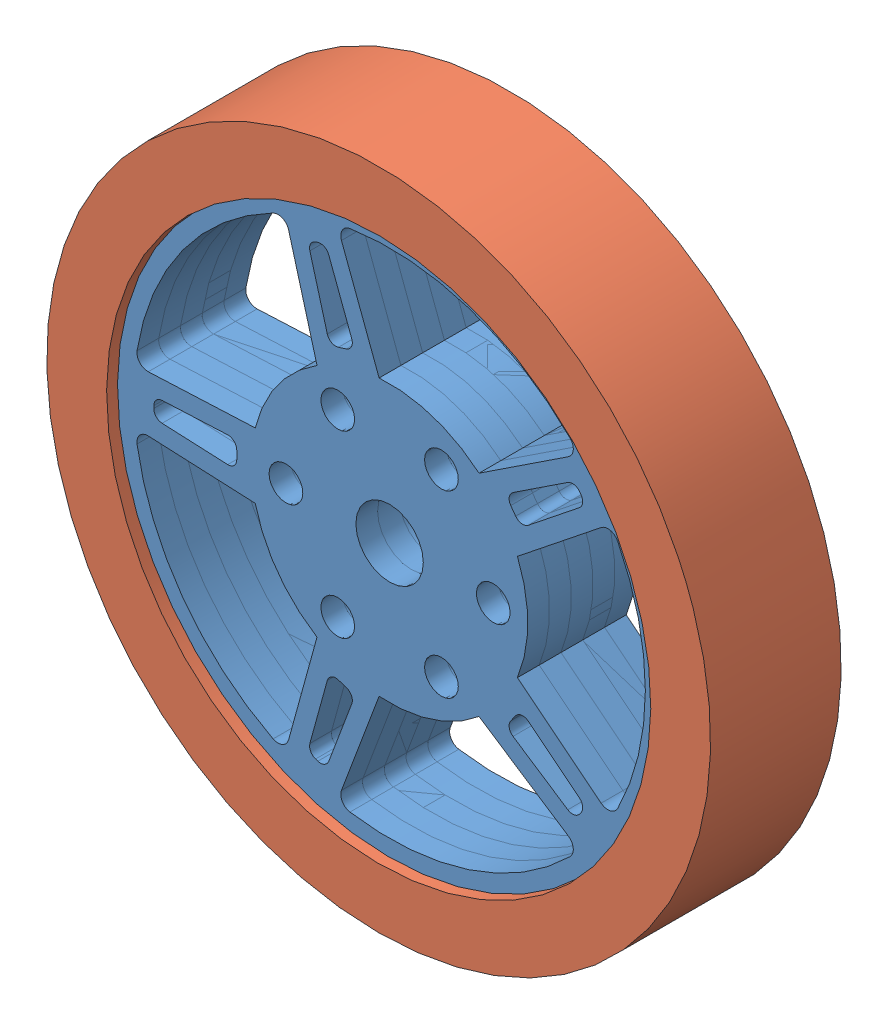
SolidWorks assembly wheel assembly, configuration Default. Lengths in mm.
Overall size (79.46 79.46 12).
10 component instances, 2 part files, 26 mates.
Components (placement in the parent):
- wheellayer-1: wheellayer [Default] at (0.056 0.28 58) x (0 1 0) z (1 0 0) size (59 2 59)
- wheellayer-3: wheellayer [Default] at (0.056 0.28 62) x (0 -1 0) z (1 0 0) size (59 2 59)
- wheellayer-4: wheellayer [Default] at (0.056 0.28 64) x (0 -1 0) z (1 0 0) size (59 2 59)
- wheellayer-5: wheellayer [Default] at (0.056 0.28 62) x (0 -1 0) z (1 0 0) size (59 2 59)
- wheellayer-6: wheellayer [Default] at (0.056 0.28 62) x (0 -1 0) z (1 0 0) size (59 2 59)
- wheellayer-7: wheellayer [Default] at (0.056 0.28 62) x (0 -1 0) z (1 0 0) size (59 2 59)
- wheellayer-9: wheellayer [Default] at (0.056 0.28 64) x (0 -1 0) z (1 0 0) size (59 2 59)
- wheellayer-11: wheellayer [Default] at (0.056 0.28 66) x (0 -1 0) z (1 0 0) size (59 2 59)
- wheellayer-14: wheellayer [Default] at (0.056 0.28 68) x (0 -1 0) z (1 0 0) size (59 2 59)
- tire-1: tire [Default] at (0.056 0.28 68) x (0.926665 0.375887 0) z (0 0 1) size (61 61 12)
Mates (geometry in assembly coordinates):
- Coincident3: coincident anti-aligned: plane of wheellayer-1 through (0.056 0.28 60) normal (0 0 1); plane of wheellayer-3 through (0.056 0.28 60) normal (0 0 -1)
- Concentric2: concentric anti-aligned: cylinder of wheellayer-1 through (0.056 0.28 60) axis (0 0 -1) radius 3.1; cylinder of wheellayer-3 through (0.056 0.28 60) axis (0 0 1) radius 3.1
- Coincident8: coincident aligned: plane of wheellayer-1 through (-9.5423 -21.1705 60) normal (-0.964079 0.265616 0); plane of wheellayer-3 through (-9.5423 -21.1705 60) normal (-0.964079 0.265616 0)
- Coincident9: coincident anti-aligned: plane of wheellayer-3 through (0.056 0.28 62) normal (0 0 1); plane of wheellayer-4 through (0.056 0.28 62) normal (0 0 -1)
- Concentric4: concentric anti-aligned: cylinder of wheellayer-1 through (0.056 0.28 60) axis (0 0 -1) radius 3.1; cylinder of wheellayer-4 through (0.056 0.28 62) axis (0 0 1) radius 3.1
- Coincident10: coincident aligned: plane of wheellayer-1 through (-9.5423 -21.1705 60) normal (-0.964079 0.265616 0); plane of wheellayer-4 through (-9.5423 -21.1705 62) normal (-0.964079 0.265616 0)
- Concentric5: concentric anti-aligned: cylinder of wheellayer-1 through (0.056 0.28 60) axis (0 0 -1) radius 3.1; cylinder of wheellayer-5 through (0.056 0.28 60) axis (0 0 1) radius 3.1
- Coincident11: coincident aligned: plane of wheellayer-1 through (-9.5423 -21.1705 60) normal (-0.964079 0.265616 0); plane of wheellayer-5 through (-9.5423 -21.1705 60) normal (-0.964079 0.265616 0)
- Coincident12: coincident anti-aligned: plane of wheellayer-1 through (0.056 0.28 60) normal (0 0 1); plane of wheellayer-5 through (0.056 0.28 60) normal (0 0 -1)
- Coincident13: coincident anti-aligned: plane of wheellayer-1 through (0.056 0.28 60) normal (0 0 1); plane of wheellayer-6 through (0.056 0.28 60) normal (0 0 -1)
- Concentric6: concentric anti-aligned: cylinder of wheellayer-1 through (0.056 0.28 60) axis (0 0 -1) radius 3.1; cylinder of wheellayer-6 through (0.056 0.28 60) axis (0 0 1) radius 3.1
- Coincident14: coincident aligned: plane of wheellayer-1 through (-9.5423 -21.1705 60) normal (-0.964079 0.265616 0); plane of wheellayer-6 through (-9.5423 -21.1705 60) normal (-0.964079 0.265616 0)
- Coincident15: coincident anti-aligned: plane of wheellayer-1 through (0.056 0.28 60) normal (0 0 1); plane of wheellayer-7 through (0.056 0.28 60) normal (0 0 -1)
- Concentric7: concentric anti-aligned: cylinder of wheellayer-1 through (0.056 0.28 60) axis (0 0 -1) radius 3.1; cylinder of wheellayer-7 through (0.056 0.28 60) axis (0 0 1) radius 3.1
- Coincident17: coincident aligned: plane of wheellayer-1 through (-9.5423 -21.1705 60) normal (-0.964079 0.265616 0); plane of wheellayer-7 through (-9.5423 -21.1705 60) normal (-0.964079 0.265616 0)
- Coincident20: coincident anti-aligned: plane of wheellayer-3 through (0.056 0.28 62) normal (0 0 1); plane of wheellayer-9 through (0.056 0.28 62) normal (0 0 -1)
- Concentric9: concentric anti-aligned: cylinder of wheellayer-1 through (0.056 0.28 60) axis (0 0 -1) radius 3.1; cylinder of wheellayer-9 through (0.056 0.28 62) axis (0 0 1) radius 3.1
- Coincident21: coincident aligned: plane of wheellayer-1 through (-9.5423 -21.1705 60) normal (-0.964079 0.265616 0); plane of wheellayer-9 through (-9.5423 -21.1705 62) normal (-0.964079 0.265616 0)
- Coincident25: coincident anti-aligned: plane of wheellayer-4 through (0.056 0.28 64) normal (0 0 1); plane of wheellayer-11 through (0.056 0.28 64) normal (0 0 -1)
- Concentric12: concentric aligned: cylinder of wheellayer-4 through (0.056 0.28 62) axis (0 0 1) radius 3.1; cylinder of wheellayer-11 through (0.056 0.28 64) axis (0 0 1) radius 3.1
- Coincident26: coincident aligned: plane of wheellayer-6 through (-9.5423 -21.1705 60) normal (-0.964079 0.265616 0); plane of wheellayer-11 through (-9.5423 -21.1705 64) normal (-0.964079 0.265616 0)
- Coincident30: coincident anti-aligned: plane of wheellayer-11 through (0.056 0.28 66) normal (0 0 1); plane of wheellayer-14 through (0.056 0.28 66) normal (0 0 -1)
- Concentric14: concentric aligned: cylinder of wheellayer-4 through (0.056 0.28 62) axis (0 0 1) radius 3.1; cylinder of wheellayer-14 through (0.056 0.28 66) axis (0 0 1) radius 3.1
- Coincident31: coincident aligned: plane of wheellayer-6 through (-9.5423 -21.1705 60) normal (-0.964079 0.265616 0); plane of wheellayer-14 through (-9.5423 -21.1705 66) normal (-0.964079 0.265616 0)
- Concentric17: concentric aligned: cylinder of wheellayer-14 through (0.056 0.28 66) axis (0 0 1) radius 29.5; cylinder of tire-1 through (0.056 0.28 58) axis (0 0 1) radius 29.5
- Coincident33: coincident anti-aligned: plane of wheellayer-1 through (0.056 0.28 58) normal (0 0 -1); plane of tire-1 through (0.056 0.28 58) normal (0 0 1)
